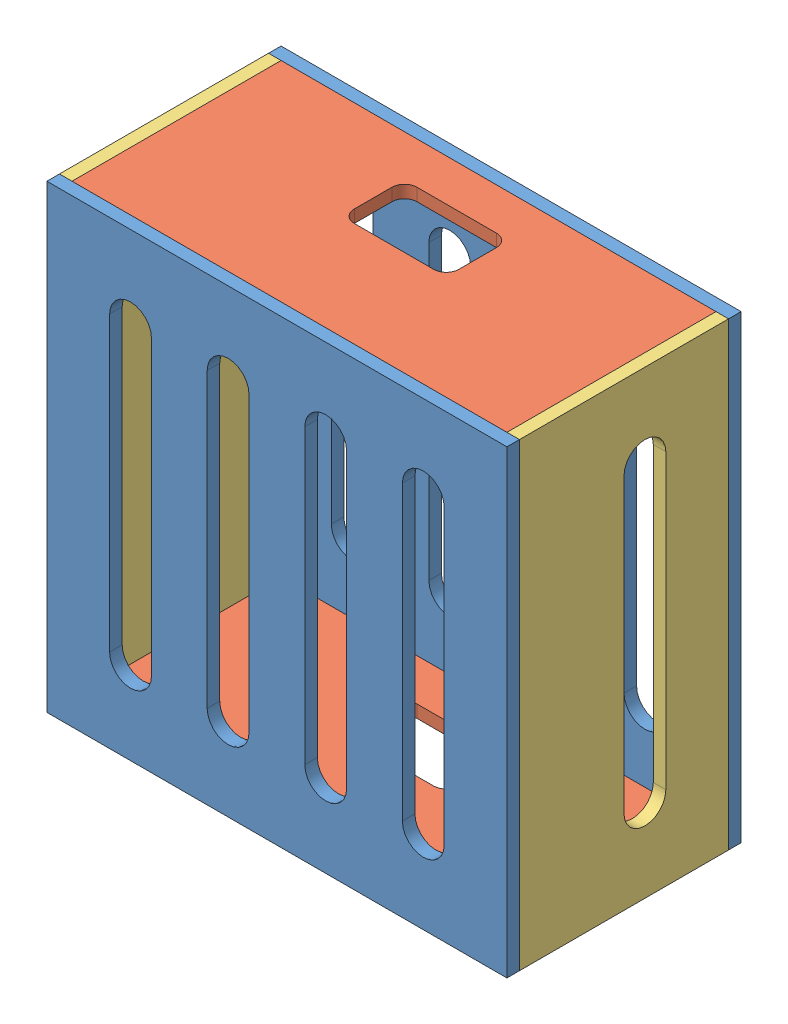
SolidWorks assembly CHARGEBOX, configuration Varsayılan. Lengths in mm.
Overall size (110 110 56).
6 component instances, 3 part files, 15 mates.
Components (placement in the parent):
- 11X11-1: 11X11 [Varsayılan] at (-45.9445 52.9877 108.5) size (110 110 3)
- 11X11-2: 11X11 [Varsayılan] at (-45.9445 52.9877 161.5) size (110 110 3)
- 104X5-5: 104X5 [Varsayılan] at (-42.9445 -57.0123 111.5) size (104 3 50)
- 11X5-5: 11X5 [Varsayılan] at (64.0555 -57.0123 111.5) x (0 1 0) z (0 0 1) size (110 3 50)
- 11X5-6: 11X5 [Varsayılan] at (-42.9445 -57.0123 111.5) x (0 1 0) z (0 0 1) size (110 3 50)
- 104X5-6: 104X5 [Varsayılan] at (-42.9445 49.9877 111.5) size (104 3 50)
Mates (geometry in assembly coordinates):
- Çakışık16: coincident anti-aligned: plane of 11X11-1 through (-45.9445 52.9877 111.5) normal (0 0 1); plane of 104X5-5 through (-42.9445 -54.0123 111.5) normal (0 0 -1)
- Çakışık17: coincident anti-aligned: plane of 11X11-2 through (-45.9445 52.9877 161.5) normal (0 0 -1); plane of 104X5-5 through (-42.9445 -54.0123 161.5) normal (0 0 1)
- Çakışık18: coincident aligned: plane of 11X11-2 through (-45.9445 -57.0123 164.5) normal (0 -1 0); plane of 104X5-5 through (-42.9445 -57.0123 111.5) normal (0 -1 0)
- Çakışık19: coincident aligned: plane of 11X11-1 through (-45.9445 -57.0123 111.5) normal (0 -1 0); plane of 104X5-5 through (-42.9445 -57.0123 111.5) normal (0 -1 0)
- Çakışık20: coincident aligned: plane of 11X11-2 through (64.0555 52.9877 164.5) normal (1 0 0); plane of 11X5-5 through (64.0555 -57.0123 111.5) normal (1 0 0)
- Çakışık22: coincident anti-aligned: plane of 11X11-1 through (-45.9445 52.9877 111.5) normal (0 0 1); plane of 11X5-5 through (61.0555 -57.0123 111.5) normal (0 0 -1)
- Çakışık23: coincident aligned: plane of 104X5-5 through (-42.9445 -57.0123 111.5) normal (0 -1 0); plane of 11X5-5 through (61.0555 -57.0123 111.5) normal (0 -1 0)
- Çakışık24: coincident anti-aligned: plane of 104X5-5 through (61.0555 -54.0123 111.5) normal (1 0 0); plane of 11X5-5 through (61.0555 -57.0123 111.5) normal (-1 0 0)
- Çakışık25: coincident anti-aligned: plane of 11X5-5 through (61.0555 -57.0123 111.5) normal (-1 0 0); plane of 104X5-6 through (61.0555 52.9877 111.5) normal (1 0 0)
- Çakışık26: coincident anti-aligned: plane of 11X11-2 through (-45.9445 52.9877 161.5) normal (0 0 -1); plane of 104X5-6 through (-42.9445 52.9877 161.5) normal (0 0 1)
- Çakışık27: coincident aligned: plane of 11X11-2 through (-45.9445 52.9877 164.5) normal (0 1 0); plane of 104X5-6 through (-42.9445 52.9877 111.5) normal (0 1 0)
- Çakışık28: coincident anti-aligned: plane of 11X5-6 through (-42.9445 -57.0123 111.5) normal (1 0 0); plane of 104X5-6 through (-42.9445 52.9877 111.5) normal (-1 0 0)
- Çakışık29: coincident anti-aligned: plane of 11X11-2 through (-45.9445 52.9877 161.5) normal (0 0 -1); plane of 11X5-6 through (-45.9445 -57.0123 161.5) normal (0 0 1)
- Çakışık30: coincident aligned: plane of 11X5-6 through (-45.9445 52.9877 111.5) normal (0 1 0); plane of 104X5-6 through (-42.9445 52.9877 111.5) normal (0 1 0)
- Çakışık31: coincident aligned: plane of 11X11-1 through (-45.9445 52.9877 111.5) normal (-1 0 0); plane of 11X5-6 through (-45.9445 -57.0123 111.5) normal (-1 0 0)
